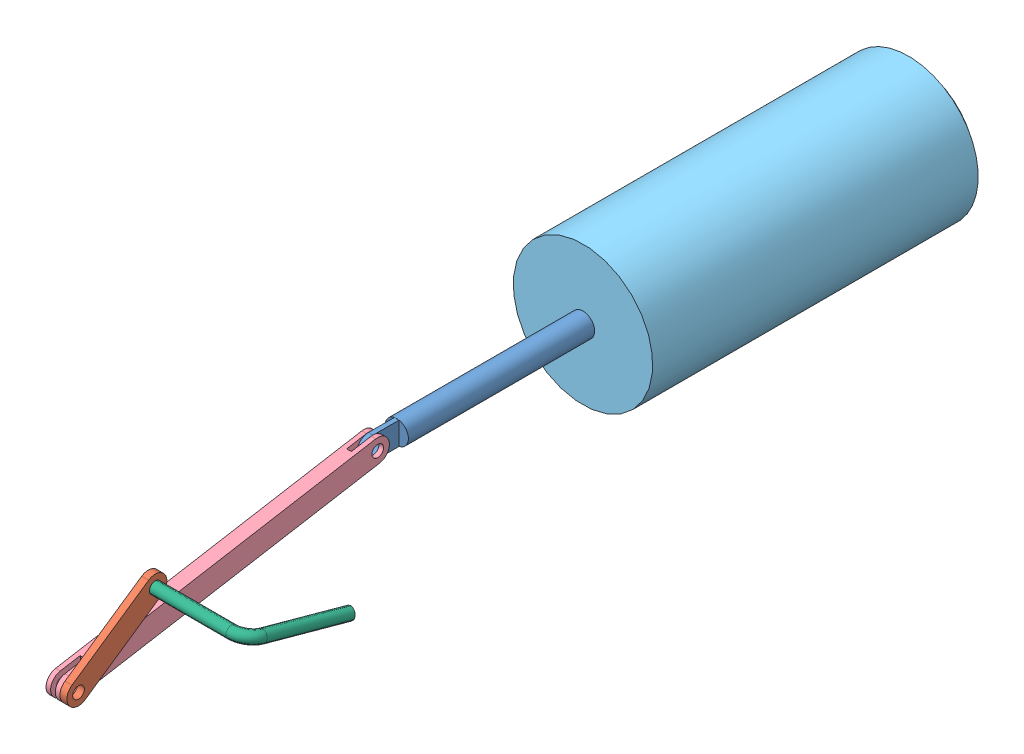
SolidWorks assembly Assembly, configuration Default. Lengths in mm.
Overall size (94.54 84.84 380.86).
6 component instances, 6 part files, 17 mates.
Components (placement in the parent):
- Bar-2: Bar [По умолчанию] at (3 43.8322 -216.0464) x (0 0 1) z (1 0 0) size (120 10 10)
- Link 1-5: Link 1 [По умолчанию] at (6 18.6961 -63.5008) x (0 -0.565193 0.824958) z (-1 0 0) size (50 10 3)
- Piston-2: Piston [По умолчанию] at (-2.5233 22.8067 -304.5228) x (0 0 1) z (-0.793156 0.609018 0) size (20 50 50)
- Link 2-3: Link 2 [По умолчанию] at (3 19.0418 -112.8011) x (0 -0.169164 0.985588) z (-1 0 0) size (143.64 10 6)
- Cylinder-2: Cylinder [По умолчанию] at (3 30 -439.943) x (0 0 1) z (0.717215 -0.696852 0) size (150.91 60 60)
- Lever-2: Lever [По умолчанию] at (37.808 31.8254 -70.5633) x (1 0 0) z (0 0.981801 -0.189915) size (49.12 43.64 5)
Mates (geometry in assembly coordinates):
- Parallel12: parallel: plane of assembly through (0 0 0) normal (0 0 1); plane of Cylinder-2 through (-0.4843 26.4139 -270) normal (0 0 1); plane of assembly
- Coincident27: coincident: circle of Bar-2; plane of Piston-2 through (-12.2255 10.1711 -289.8951) normal (0 0 1)
- Concentric21: concentric: circle of Bar-2; circle of Piston-2
- Concentric22: concentric: cylinder of Bar-2 through (3 30 -289.8951) axis (0 0 -1) radius 5; cylinder of Cylinder-2 through (3 30 -439.943) axis (0 0 1) radius 5
- Parallel10: parallel: plane of assembly through (0 0 0) normal (1 0 0); plane of Bar-2 through (2 43.8322 -169.8951) normal (-1 0 0); plane of assembly
- Coincident35: coincident: plane of Bar-2 through (4 43.8322 -169.8951) normal (1 0 0); plane of Link 2-3 through (4 19.0418 -112.8011) normal (-1 0 0)
- Concentric23: concentric: cylinder of Bar-2 through (-5.0711 30 -178.7193) axis (1 0 0) radius 2.5; cylinder of Link 2-3 through (4 30 -178.7193) axis (1 0 0) radius 2.5
- LimitDistance2: limit distance = 14.8951 mm: plane of Piston-2 through (-12.2255 10.1711 -289.8951) normal (0 0 1); plane of Cylinder-2 through (-14.4213 12.0696 -275) normal (0 0 -1)
- Coincident42: coincident: plane of assembly through (0 0 -270) normal (0 0 1); plane of Cylinder-2 through (-0.4843 26.4139 -270) normal (0 0 1); plane of assembly
- Tangent2: tangent: cylinder of assembly; cylinder of Cylinder-2 through (3 30 -439.943) axis (0 0 1) radius 30; plane of assembly
- LimitDistance9: limit distance = 80.1049 mm: plane of Bar-2 through (3 25 -189.8951) normal (0 0 1); plane of Cylinder-2 through (-0.4843 26.4139 -270) normal (0 0 1)
- Coincident43: coincident: plane of Link 1-5 through (6 18.6961 -63.5008) normal (-1 0 0); plane of Link 2-3 through (6 19.0418 -112.8011) normal (1 0 0)
- Concentric29: concentric: cylinder of Link 1-5 through (27.0278 7.3923 -47.0017) axis (-1 0 0) radius 2.5; cylinder of Link 2-3 through (4 7.3923 -47.0017) axis (1 0 0) radius 2.5
- Concentric30: concentric: cylinder of Link 1-5 through (27.0278 30 -80) axis (-1 0 0) radius 2.5; cylinder of Lever-2 through (41.8685 30 -80) axis (-1 0 0) radius 2.5
- Coincident44: coincident: plane of Link 1-5 through (6 18.6961 -63.5008) normal (-1 0 0); plane of Lever-2 through (6 30 -80) normal (-1 0 0)
- Coincident45: coincident: plane of assembly through (0 0 0) normal (1 0 0); plane of Link 2-3 through (0 19.0418 -112.8011) normal (-1 0 0); plane of assembly
- Concentric33: concentric: cylinder of assembly; cylinder of Lever-2 through (41.8685 30 -80) axis (-1 0 0) radius 2.5; line of assembly
